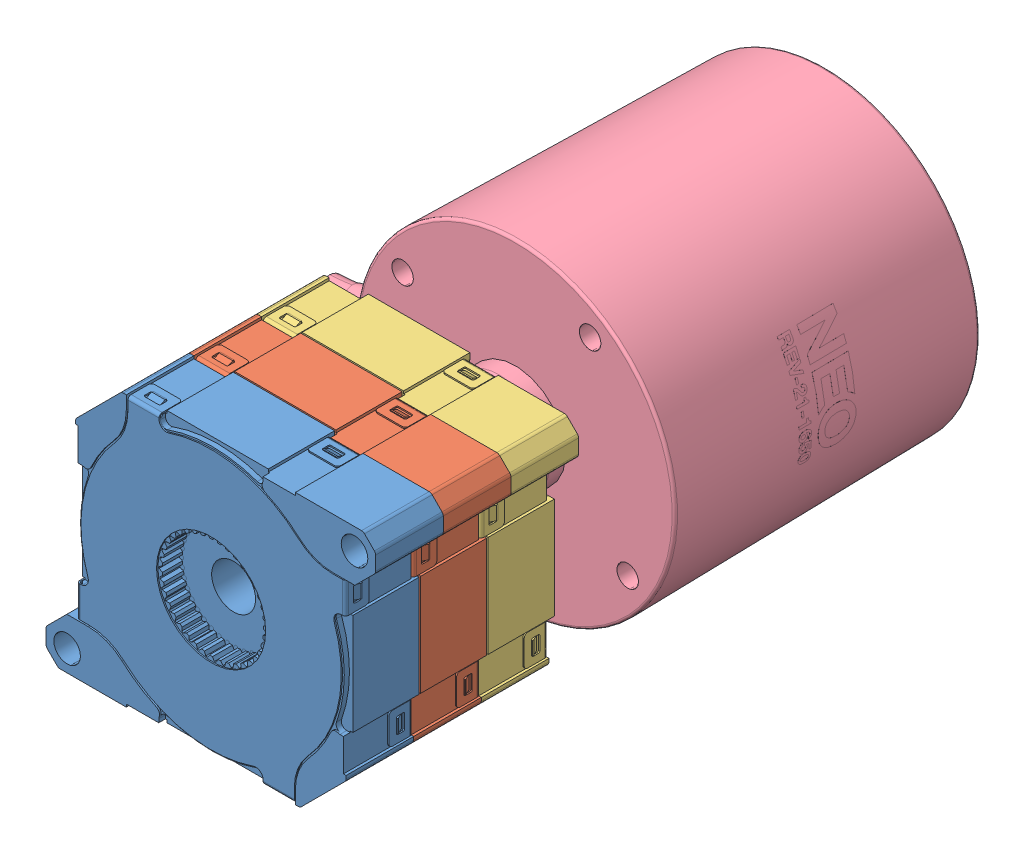
SolidWorks assembly MAXPlanetary 3-Stage.STEP, configuration Default. Lengths in mm.
Overall size (94.51 94.05 133.55).
9 component instances, 7 part files, 0 mates.
Components (placement in the parent):
- REV-25-2109_3-Stage (No Shaft, For NEO).STEP-2: REV-25-2109_3-Stage (No Shaft, For NEO).STEP [Default] at origin
  - REV-25-2107_3-Stage.STEP-1: REV-25-2107_3-Stage.STEP [Default] at (0 0 6.35) x (-1 0 0) z (0 0 -1) (suppressed, hidden)
  - REV-21-2106.STEP-1: REV-21-2106.STEP [Default] at origin (suppressed, hidden)
  - REV-21-2104.STEP-1: REV-21-2104.STEP [Default] at (0 0 57.15) x (0 0 1) z (-1 0 0) (suppressed, hidden)
  - REV-21-2108.STEP-1: REV-21-2108.STEP [Default] at (0 0 7.0985) x (-0.554615 -0.832107 0) z (0 0 -1) (suppressed, hidden)
- REV-21-2101.stp-2: REV-21-2101.stp [Default] at (0 0 41.275) size (61.91 50.8 16.85)
- REV-21-2102.stp-2: REV-21-2102.stp [Default] at (0 0 28.575) size (94.05 94.05 94.05)
- REV-21-2103.stp-2: REV-21-2103.stp [Default] at (0 0 15.875) size (61.91 50.8 16.85)
- REV-21-1650.stp-2: REV-21-1650.stp [Default] at (0 0 -9.525) x (0.554615 0.832107 0) z (0 0 1) size (64.41 64.76 93.26)
